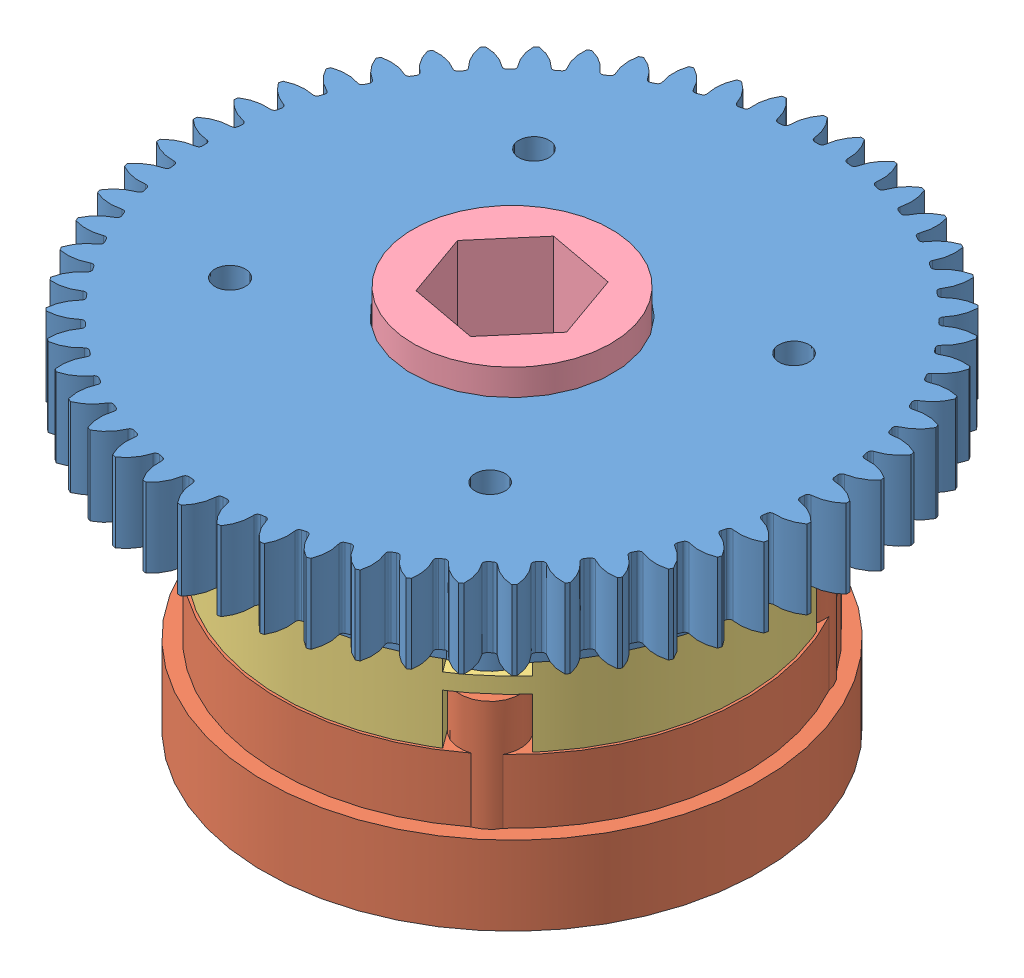
SolidWorks assembly planetery, configuration Default. Lengths in mm.
Overall size (66.96 27.26 66.96).
7 component instances, 5 part files, 17 mates.
Components (placement in the parent):
- anel-1: anel [Default] at (45.7381 21.875 -95.0766) x (-0.151413 0 0.988471) z (0 1 0) size (58.74 58.74 9.93)
- anel 2-1: anel 2 [Default] at (45.7381 2.705 -95.0766) x (-0.151413 0 0.988471) z (0 -1 0) size (34 34 13.02)
- middle part of the planetery-1: middle part of the planetery [Default] at (45.7381 13.25 -95.0766) x (-0.151413 0 0.988471) z (-0.988471 0 -0.151413) size (31.65 7.5 31.65)
- planeta-1: planeta [Default] at (45.7381 15.78 -95.0766) x (0.760248 0 0.649633) z (0 1 0) size (22.25 22.25 10.13)
- sol-1: sol [Default] at (44.3761 11.835 -86.1853) x (-0.794258 -0.595274 -0.121664) z (-0.151413 0 0.988471) size (14.26 14.26 9.75)
- planeta-2: planeta [Default] at (45.7381 7.6 -95.0766) x (-0.711665 0 -0.702519) z (0 -1 0) size (22.25 22.25 10.13)
- sol-2: sol [Default] at (47.1001 11.835 -103.9679) x (0.156526 0.987383 0.023976) z (0.151413 0 -0.988471) size (14.26 14.26 9.75)
Mates (geometry in assembly coordinates):
- Concentric1: concentric aligned: circle of anel 2-1; cylinder of planeta-2 through (45.7381 -1.94 -95.0766) axis (0 1 0) radius 6.8
- Coincident5: coincident anti-aligned: plane of anel 2-1 through (45.7381 2.8 -95.0766) normal (0 1 0); plane of planeta-2 through (45.7381 2.8 -95.0766) normal (0 -1 0)
- Tangent2: tangent anti-aligned: plane of middle part of the planetery-1 through (45.7381 13.25 -95.0766) normal (0 -1 0); cylinder of sol-1 through (45.0954 11.835 -90.8806) axis (-0.151413 0 0.988471) radius 1.415
- Coincident9: coincident anti-aligned: plane of middle part of the planetery-1 through (43.9219 15.25 -83.2199) normal (0.151413 0 -0.988471); plane of sol-1 through (43.9219 11.835 -83.2199) normal (-0.151413 0 0.988471)
- Tangent3: tangent: cylinder of sol-1 through (45.0954 11.835 -90.8806) axis (-0.151413 0 0.988471) radius 1.415; line of middle part of the planetery-1 through (48.1342 13.25 -110.7192) axis (-0.151413 0 0.988471)
- Tangent4: tangent anti-aligned: plane of middle part of the planetery-1 through (45.7381 13.25 -95.0766) normal (0 -1 0); cylinder of sol-2 through (46.3809 11.835 -99.2727) axis (0.151413 0 -0.988471) radius 1.415
- Coincident12: coincident: line of middle part of the planetery-1 through (48.1342 13.25 -110.7192) axis (-0.151413 0 0.988471); cylinder of sol-2 through (46.3809 11.835 -99.2727) axis (0.151413 0 -0.988471) radius 1.415
- Coincident13: coincident anti-aligned: plane of middle part of the planetery-1 through (47.5543 15.25 -106.9333) normal (-0.151413 0 0.988471); plane of sol-2 through (47.5543 11.835 -106.9333) normal (0.151413 0 -0.988471)
- Concentric2: concentric aligned: cylinder of anel 2-1 through (33.8135 0 -87.6465) axis (0 1 0) radius 1.04; circle of middle part of the planetery-1
- Concentric3: concentric aligned: circle of anel 2-1; circle of middle part of the planetery-1
- Coincident14: coincident anti-aligned: plane of anel 2-1 through (45.7381 9.8 -95.0766) normal (0 1 0); plane of middle part of the planetery-1 through (45.7381 9.8 -95.0766) normal (0 -1 0)
- Concentric4: concentric aligned: cylinder of anel-1 through (45.7381 24.58 -95.0766) axis (0 -1 0) radius 6.9; cylinder of planeta-1 through (45.7381 25.32 -95.0766) axis (0 -1 0) radius 6.8
- Coincident15: coincident anti-aligned: circle of anel-1; plane of planeta-1 through (45.7381 20.58 -95.0766) normal (0 1 0)
- Coincident17: coincident anti-aligned: plane of anel 2-1 through (45.7381 0 -95.0766) normal (0 -1 0)
- Concentric9: concentric anti-aligned: circle of anel-1; circle of middle part of the planetery-1
- Concentric10: concentric anti-aligned: circle of anel-1; circle of middle part of the planetery-1
- Coincident23: coincident anti-aligned: plane of anel-1 through (45.7381 15.25 -95.0766) normal (0 -1 0); plane of middle part of the planetery-1 through (45.7381 15.25 -95.0766) normal (0 1 0)
